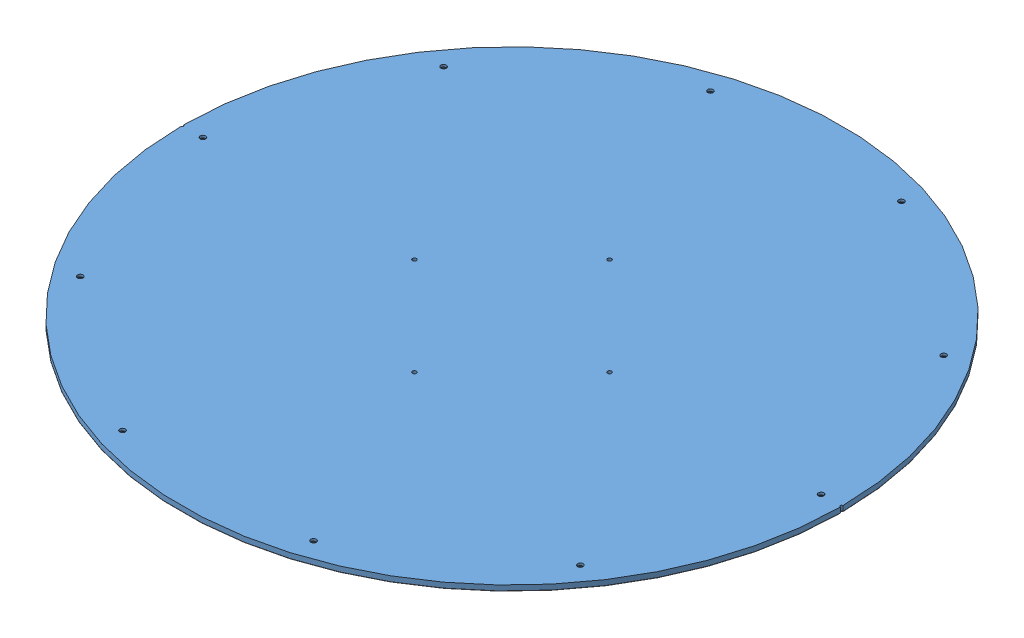
SolidWorks assembly GE-20106, configuration Default. Lengths in mm.
Overall size (812.79 6.6 812.8).
2 component instances, 2 part files, 6 mates.
Components (placement in the parent):
- GE-20107-1: GE-20107 [Default] x (-1 0 0) z (0 0 1) size (812.79 6.35 812.8)
- GE-20106-vinyl-1: GE-20106-vinyl [Default] at (0 -0.254 0) x (1 0 0) z (0 0 -1) size (812.79 0.25 812.8)
Mates (geometry in assembly coordinates):
- Coincident11: coincident aligned: plane of GE-20107-1 through (0 0 0) normal (0 1 0)
- Coincident12: coincident anti-aligned: plane of GE-20107-1 through (0 0 0) normal (-1 0 0)
- Coincident13: coincident aligned: plane of GE-20107-1 through (0 0 0) normal (0 0 1)
- Coincident14: coincident anti-aligned: plane of GE-20107-1 through (0 -6.35 0) normal (0 -1 0); plane of GE-20106-vinyl-1 through (203.2 -6.35 0) normal (0 1 0)
- Concentric1: concentric aligned: cylinder of GE-20107-1 through (0 -6.35 0) axis (0 1 0) radius 406.4; cylinder of GE-20106-vinyl-1 through (0 -6.604 0) axis (0 1 0) radius 406.4
- Concentric2: concentric aligned: cylinder of GE-20106-vinyl-1 through (-120.2563 -6.604 0) axis (0 -1 0) radius 2.4574; cylinder of GE-20107-1 through (-120.2563 -6.35 0) axis (0 -1 0) radius 2.4574
